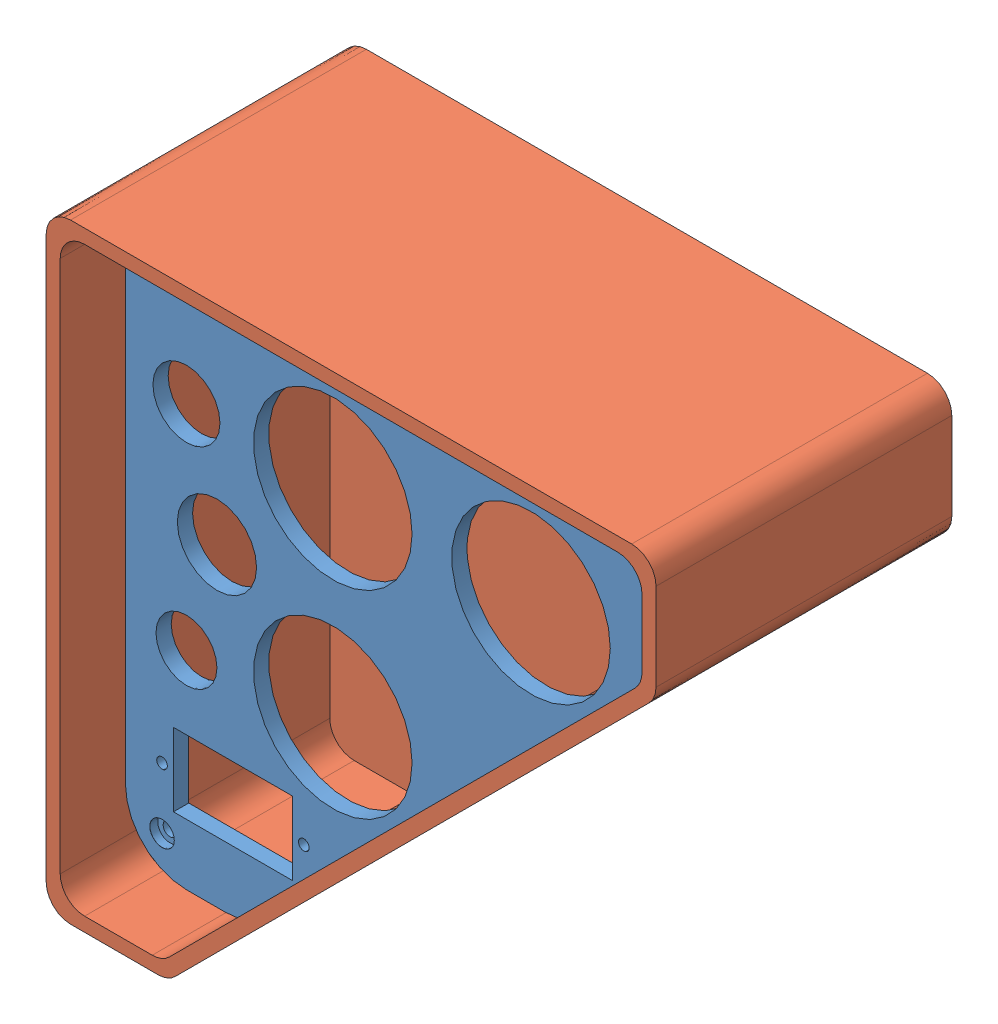
SolidWorks assembly prova4, configuration Default. Lengths in mm.
Overall size (200 200 97).
2 component instances, 2 part files, 3 mates.
Components (placement in the parent):
- layer2-1: layer2 [Default] at (-125.0984 -105.6863 -2.5) size (183 188 5)
- base prova-1: base prova [Default] at (-129.6984 -113.0863 -73.1) size (200 200 97)
Mates (geometry in assembly coordinates):
- Coincidente1: coincident: plane of layer2-1 through (-105.0984 62.3137 -2.5) normal (0 0 -1); plane of base prova-1 through (-79.8212 82.3137 -2.5) normal (0 0 1)
- Coincidente2: coincident: plane of layer2-1 through (-105.0984 82.3137 2.5) normal (0 1 0); plane of base prova-1 through (94.9788 82.3137 -64.5) normal (0 -1 0)
- Coincidente3: coincident: line of layer2-1 through (-125.0984 62.3137 2.5) axis (0 -1 0); plane of base prova-1 through (-87.8212 74.3137 -64.5) normal (1 0 0)
